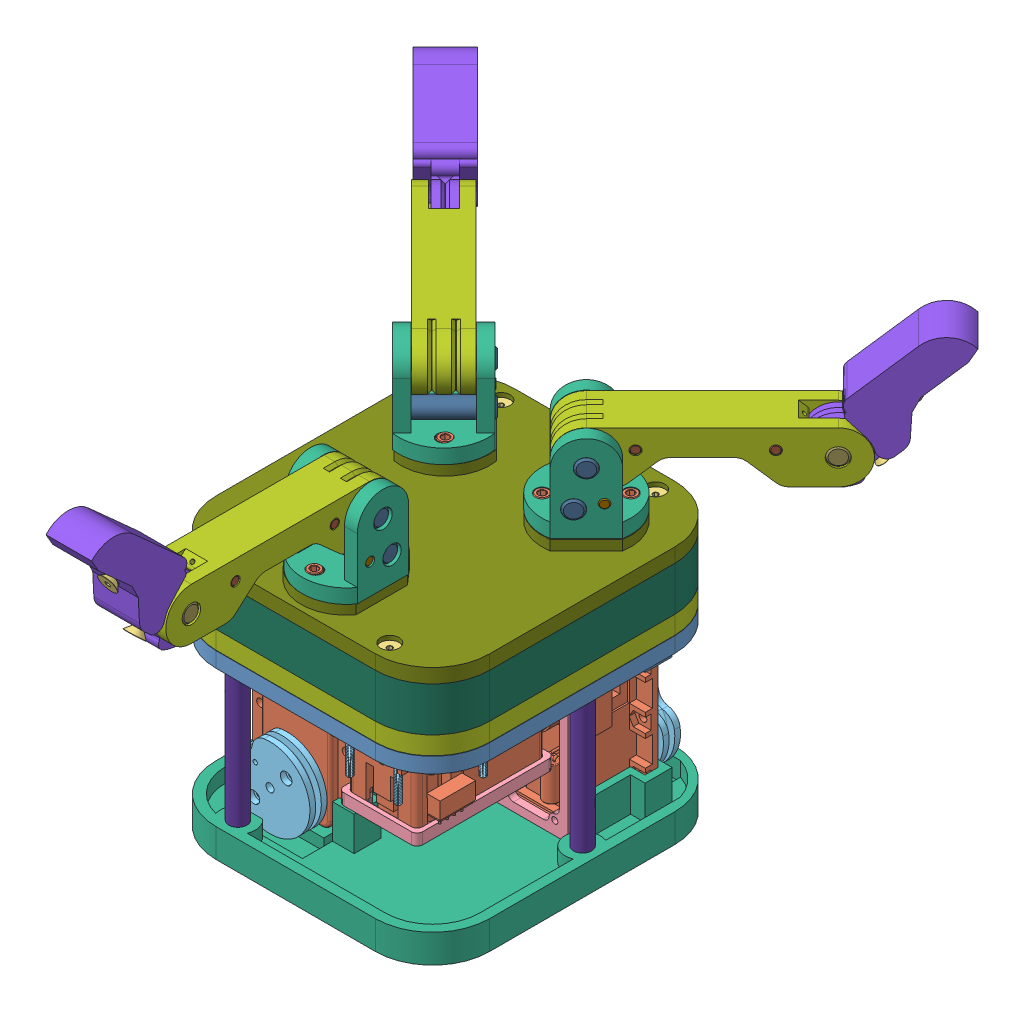
SolidWorks assembly hand_model, configuration Default. Lengths in mm.
Overall size (458.66 261.05 528.52).
145 component instances, 30 part files, 23 mates.
Components (placement in the parent):
- wrist_block_final-1: wrist_block_final [Default] at (38.9884 111.7259 8.2191) x (-1 0 0) z (0 0 1) size (96.58 286.67 158.34)
  - w1-1: w1 [Default] at (-5.748 25.854 -30.7534) size (96 184.32 158.34)
    - w_t1_test-1: w_t1_test [Default] at (30.6952 9.3465 110.579) size (96 12.88 105)
    - gear_MX-28-1: gear_MX-28 [Default] at (18.9956 62.9761 161.9587) x (-1 0 0) z (0 -1 0) size (35.6 52.23 39.77)
      - dynamixel MX-28-exposed-1: dynamixel MX-28-exposed [Back Off] at (8.6005 39.3797 35.4547) size (35.6 50.6 39.77)
      - w_g1-2: w_g1 [Default] at (8.6005 39.3797 55.9747) size (25.49 25.49 3)
      - w_ac-1: w_ac [Default] at (20.9755 51.5047 26.7047) x (0 -1 0) z (0 0 -1) size (48.25 27.65 4)
    - pulley_MX-28-1: pulley_MX-28 [Default] at (51.4952 51.1215 127.129) size (38.36 58.4 108.06)
      - dynamixel MX-28-exposed-1: dynamixel MX-28-exposed [Back Off] at origin size (35.6 50.6 39.77)
      - w_p1-1: w_p1 [Default] at (0 0 23.67) x (0.707107 -0.707107 0) z (0 0 1) size (26.25 28 6)
      - w_ac-1: w_ac [Default] at (12.375 12.125 -8.75) x (0 -1 0) z (0 0 -1) size (48.25 27.65 4)
    - pulley_MX-28-2: pulley_MX-28 [Default] at (51.4952 51.1215 92.029) x (-1 0 0) z (0 0 -1) size (38.36 58.4 108.06)
      - dynamixel MX-28-exposed-1: dynamixel MX-28-exposed [Back Off] at origin size (35.6 50.6 39.77)
      - w_p1-1: w_p1 [Default] at (0 0 23.67) x (0.707107 -0.707107 0) z (0 0 1) size (26.25 28 6)
      - w_ac-1: w_ac [Default] at (12.375 12.125 -8.75) x (0 -1 0) z (0 0 -1) size (48.25 27.65 4)
    - pulley_MX-28-3: pulley_MX-28 [Default] at (9.8952 51.1215 92.029) x (-1 0 0) z (0 0 -1) size (38.36 58.4 108.06)
      - dynamixel MX-28-exposed-1: dynamixel MX-28-exposed [Back Off] at origin size (35.6 50.6 39.77)
      - w_p1-1: w_p1 [Default] at (0 0 23.67) x (0.707107 -0.707107 0) z (0 0 1) size (26.25 28 6)
      - w_ac-1: w_ac [Default] at (12.375 12.125 -8.75) x (0 -1 0) z (0 0 -1) size (48.25 27.65 4)
    - w_b1-1: w_b1 [Default] at (30.6952 70.6215 113.079) x (-1 0 0) z (0 0 1) size (96 17 105)
  - w2-1: w2 [Default] at (-13.7396 -16.4115 -4.4526) size (96 129.36 105)
    - w_t2-1: w_t2 [Default] at (38.6868 42.912 84.2782) size (96 6.36 105)
    - w_g2-1: w_g2 [Default] at (35.3573 46.267 79.3076) x (1 0 0) z (0 1 0) size (25.39 25.39 5.6)
    - w_g3-1: w_g3 [Default] at (71.6818 49.267 106.8682) x (1 0 0) z (0 -1 0) size (25.39 25.39 14.76)
    - w_g2-2: w_g2 [Default] at (48.9868 46.267 99.0621) x (0.999627 0 -0.027307) z (0 1 0) size (25.39 25.39 5.6)
    - w_g3-2: w_g3 [Default] at (49.1868 49.267 59.6927) x (-1 0 0) z (0 -1 0) size (25.39 25.39 14.76)
    - t_b3-1: t_b3 [Default] at (60.4377 35.807 114.6932) x (-1 0 0) z (0 1 0) size (28.8 6.3 6.91)
    - t_b4-1: t_b4 [Default] at (49.1868 35.807 51.8677) x (1 0 0) z (0 1 0) size (26.95 6.4 6.91)
    - t_block-1: t_block [Default] at (73.2381 52.5646 52.8296) x (0 1 0) z (1 0 0) size (7.5 23.31 19.7)
      - t_b1-1: t_b1 [Default] at (-13.3027 14.296 -11.9013) size (7.5 5 19.7)
      - t_b2-1: t_b2 [Default] at (-13.3027 17.296 -3.2513) x (0.623302 0 0.781981) z (0.781981 0 -0.623302) size (4.4 3 4.4)
    - t_block-2: t_block [Default] at (31.6381 52.5646 52.8296) x (0 1 0) z (1 0 0) size (7.5 23.31 19.7)
      - t_b1-1: t_b1 [Default] at (-13.3027 14.296 -11.9013) size (7.5 5 19.7)
      - t_b2-1: t_b2 [Default] at (-13.3027 17.296 -3.2513) x (0.623302 0 0.781981) z (0.781981 0 -0.623302) size (4.4 3 4.4)
    - t_block-3: t_block [Default] at (45.7305 52.5646 116.8117) x (0 1 0) z (-1 0 0) size (7.5 23.31 19.7)
      - t_b1-1: t_b1 [Default] at (-13.3027 14.296 -11.9013) size (7.5 5 19.7)
      - t_b2-1: t_b2 [Default] at (-13.3027 17.296 -3.2513) x (0.623302 0 0.781981) z (0.781981 0 -0.623302) size (4.4 3 4.4)
    - t_b5-1: t_b5 [Default] at (28.3868 42.712 50.6927) x (-1 0 0) z (0 0 1) size (4 9.6 8.15)
    - t_b5-2: t_b5 [Default] at (69.9868 42.712 50.6927) x (-1 0 0) z (0 0 1) size (4 9.6 8.15)
    - t_b5-3: t_b5 [Default] at (48.9818 42.712 115.8682) x (1 0 0) z (0 0 -1) size (4 9.6 8.15)
    - t_b4-2: t_b4 [Default] at (49.1868 42.717 51.8677) x (-1 0 0) z (0 -1 0) size (26.95 6.4 6.91)
  - w_t3-1: w_t3 [Default] at (24.9472 17.3505 82.3256) size (96 15.5 105)
  - w_t4-1: w_t4 [Default] at (50.4615 57.3787 69.1823) size (96 10.4 105)
  - al_female_round_standoff-1: al_female_round_standoff [93330A483] at (51.0893 61.0755 128.9678) x (0.137901 0 0.990446) z (0 1 0) size (6.35 6.35 51.38)
  - al_female_round_standoff-2: al_female_round_standoff [93330A483] at (-17.195 61.0755 76.3256) x (0.680091 0 -0.733128) z (0 1 0) size (6.35 6.35 51.38)
  - al_female_round_standoff-3: al_female_round_standoff [93330A483] at (67.0893 61.0755 76.3256) x (0.609984 0 -0.792414) z (0 1 0) size (6.35 6.35 51.38)
  - al_female_round_standoff-4: al_female_round_standoff [93330A483] at (24.9472 61.0755 35.6835) x (1 0 0) z (0 1 0) size (6.35 6.35 51.38)
  - st_fh_sc_screw_8_32-1: st_fh_sc_screw_8_32 [92210A197] at (-17.195 96.4755 76.3256) x (0.989952 0 -0.141402) z (0 1 0) size (9.12 9.12 19.5)
  - st_fh_sc_screw_8_32-2: st_fh_sc_screw_8_32 [92210A197] at (-17.195 27.0005 76.3235) x (0.178781 0 -0.983889) z (0 -1 0) size (9.12 9.12 19.5)
  - st_fh_sc_screw_8_32-3: st_fh_sc_screw_8_32 [92210A197] at (51.0893 96.4755 128.9678) x (0.989952 0 -0.141402) z (0 1 0) size (9.12 9.12 19.5)
  - st_fh_sc_screw_8_32-4: st_fh_sc_screw_8_32 [92210A197] at (24.9472 96.4755 35.6835) x (0.989952 0 -0.141402) z (0 1 0) size (9.12 9.12 19.5)
  - st_fh_sc_screw_8_32-5: st_fh_sc_screw_8_32 [92210A197] at (67.0893 27.0005 76.3235) x (-0.751419 0 -0.659826) z (0 -1 0) size (9.12 9.12 19.5)
  - st_fh_sc_screw_8_32-6: st_fh_sc_screw_8_32 [92210A197] at (51.0893 27.0005 128.9678) x (-0.44773 0 0.894169) z (0 -1 0) size (9.12 9.12 19.5)
  - st_fh_sc_screw_8_32-7: st_fh_sc_screw_8_32 [92210A197] at (67.0893 96.4755 76.3256) x (0.989952 0 -0.141402) z (0 1 0) size (9.12 9.12 19.5)
  - st_fh_sc_screw_8_32-8: st_fh_sc_screw_8_32 [92210A197] at (24.9472 27.0005 35.6835) x (-0.751419 0 -0.659826) z (0 -1 0) size (9.12 9.12 19.5)
  - heat_sink_insert-17: heat_sink_insert [93365A120] at (52.0893 11.0005 35.6835) x (-0.837169 0 -0.546944) z (-0.546944 0 0.837169) size (4.37 3.82 4.37)
  - heat_sink_insert-18: heat_sink_insert [93365A120] at (-2.195 11.0005 128.9678) x (-0.837169 0 -0.546944) z (-0.546944 0 0.837169) size (4.37 3.82 4.37)
  - heat_sink_insert-3: heat_sink_insert [93365A120] at (52.0893 11.0005 128.9678) x (-0.837169 0 -0.546944) z (-0.546944 0 0.837169) size (4.37 3.82 4.37)
  - heat_sink_insert-4: heat_sink_insert [93365A120] at (-2.195 11.0005 35.6835) x (-0.837169 0 -0.546944) z (-0.546944 0 0.837169) size (4.37 3.82 4.37)
  - heat_sink_insert-5: heat_sink_insert [93365A120] at (39.9472 26.5005 36.5756) x (-0.837169 0 -0.546944) z (-0.546944 0 0.837169) size (4.37 3.82 4.37)
  - heat_sink_insert-6: heat_sink_insert [93365A120] at (-16.3028 26.5005 112.3256) x (-0.837169 0 -0.546944) z (-0.546944 0 0.837169) size (4.37 3.82 4.37)
  - heat_sink_insert-7: heat_sink_insert [93365A120] at (66.1378 26.5005 119.9956) x (-0.837169 0 -0.546944) z (-0.546944 0 0.837169) size (4.37 3.82 4.37)
  - heat_sink_insert-8: heat_sink_insert [93365A120] at (-16.3028 26.5005 52.3256) x (-0.973084 0 -0.230449) z (-0.230449 0 0.973084) size (4.37 3.82 4.37)
  - st_sh_screw_4_40-1: st_sh_screw_4_40 [92185A106] at (39.9472 30.5953 36.5756) x (1 0 0) z (0 1 0) size (4.65 4.65 9.43)
  - st_sh_screw_4_40-2: st_sh_screw_4_40 [92185A106] at (-16.3028 30.5953 112.3256) x (1 0 0) z (0 1 0) size (4.65 4.65 9.43)
  - st_sh_screw_4_40-3: st_sh_screw_4_40 [92185A106] at (66.1378 30.5953 119.9956) x (1 0 0) z (0 1 0) size (4.65 4.65 9.43)
  - st_sh_screw_4_40-5: st_sh_screw_4_40 [92185A106] at (-16.3028 30.5953 52.3256) x (1 0 0) z (0 1 0) size (4.65 4.65 9.43)
  - heat_sink_insert-15: heat_sink_insert [93365A120] at (24.9472 2.5005 128.3256) x (-0.837169 0 -0.546944) z (-0.546944 0 0.837169) size (4.37 3.82 4.37)
  - heat_sink_insert-16: heat_sink_insert [93365A120] at (7.9766 2.5005 65.3551) x (-0.837169 0 -0.546944) z (-0.546944 0 0.837169) size (4.37 3.82 4.37)
  - heat_sink_insert-11: heat_sink_insert [93365A120] at (-7.5798 2.5005 49.7987) x (-0.837169 0 -0.546944) z (-0.546944 0 0.837169) size (4.37 3.82 4.37)
  - heat_sink_insert-12: heat_sink_insert [93365A120] at (24.9472 2.5005 106.3256) x (-0.505917 0 -0.862582) z (-0.862582 0 0.505917) size (4.37 3.82 4.37)
  - heat_sink_insert-13: heat_sink_insert [93365A120] at (41.9177 2.5005 65.3551) x (-0.581099 0 -0.813833) z (-0.813833 0 0.581099) size (4.37 3.82 4.37)
  - heat_sink_insert-14: heat_sink_insert [93365A120] at (57.4741 2.5005 49.7987) x (-0.837169 0 -0.546944) z (-0.546944 0 0.837169) size (4.37 3.82 4.37)
  - st_fh_sc_screw_4_40-1: st_fh_sc_screw_4_40 [91253A106] at (-2.195 7.5005 128.9678) x (1 0 0) z (0 -1 0) size (6.48 6.48 6.63)
  - st_fh_sc_screw_4_40-2: st_fh_sc_screw_4_40 [91253A106] at (52.0893 7.5005 128.9678) x (1 0 0) z (0 -1 0) size (6.48 6.48 6.63)
  - st_fh_sc_screw_4_40-3: st_fh_sc_screw_4_40 [91253A106] at (52.0893 7.5005 35.6835) x (1 0 0) z (0 -1 0) size (6.48 6.48 6.63)
  - st_fh_sc_screw_4_40-4: st_fh_sc_screw_4_40 [91253A106] at (-2.195 7.5005 35.6835) x (1 0 0) z (0 -1 0) size (6.48 6.48 6.63)
  - st_hex_nut_2_56-1: st_hex_nut_2_56 [90480A003] at (13.1472 41.6693 127.6256) size (4.76 1.94 5.5)
  - st_sh_cscrew_2_56-1: st_sh_cscrew_2_56 [92196A084] at (13.1472 54.7505 127.6256) x (0.985498 0 -0.169684) z (0 1 0) size (3.56 3.56 21.57)
  - st_sh_cscrew_2_56-2: st_sh_cscrew_2_56 [92196A084] at (-10.3528 54.7505 104.3256) x (0.985498 0 -0.169684) z (0 1 0) size (3.56 3.56 21.57)
  - st_sh_cscrew_2_56-3: st_sh_cscrew_2_56 [92196A084] at (-3.8528 54.7505 127.6256) x (0.985498 0 -0.169684) z (0 1 0) size (3.56 3.56 21.57)
  - st_sh_cscrew_2_56-4: st_sh_cscrew_2_56 [92196A084] at (19.6472 54.7505 104.3256) x (0.985498 0 -0.169684) z (0 1 0) size (3.56 3.56 21.57)
  - st_hex_nut_2_56-2: st_hex_nut_2_56 [90480A003] at (-10.3528 41.6693 104.3256) size (4.76 1.94 5.5)
  - st_hex_nut_2_56-3: st_hex_nut_2_56 [90480A003] at (19.6472 41.6693 104.3256) x (0.910241 0 -0.41408) z (0.41408 0 0.910241) size (4.76 1.94 5.5)
  - st_hex_nut_2_56-5: st_hex_nut_2_56 [90480A003] at (-3.8528 41.6693 127.6256) x (0.924033 0 -0.382313) z (0.382313 0 0.924033) size (4.76 1.94 5.5)
- finger_block-1: finger_block [Default] at (-118.6928 127.742 224.9233) x (-1 0 0) z (0 0 -1) size (122.28 138.04 251.99)
  - f_k1-1: f_k1 [Default] at (-133.1387 2.8358 99.3785) size (25.4 30.39 31.13)
  - f_d1-1: f_d1 [Default] at (-133.1137 2.8358 99.3785) size (16 18 80.5)
  - f_d2-1: f_d2 [Default] at (-132.7637 2.8358 36.8785) x (1 0 0) z (0 -0.669077 0.743193) size (16 23.57 57.08)
  - 98381A475-1: 98381A475 [98381A475] at (-132.8212 -7.9267 94.8785) x (1 0 0) z (0 -0.886717 0.462312) size (25.4 3.17 3.17)
  - 98381A542-1: 98381A542 [98381A542] at (-132.5037 -9.6416 102.5535) x (1 0 0) z (0 -0.999996 0.002882) size (25.4 6.35 6.35)
  - 98381A542-2: 98381A542 [98381A542] at (-132.5037 2.8358 99.3785) x (1 0 0) z (0 -0.486508 0.873676) size (25.4 6.35 6.35)
  - heat_sink_insert-1: heat_sink_insert [93365A120] at (-133.1137 -6.1642 48.3785) x (-0.837169 0 -0.546944) z (-0.546944 0 0.837169) size (4.37 3.82 4.37)
  - heat_sink_insert-2: heat_sink_insert [93365A120] at (-133.1137 6.6358 70.6285) x (-0.837169 0 -0.546944) z (-0.546944 0 0.837169) size (4.37 3.82 4.37)
  - heat_sink_insert-3: heat_sink_insert [93365A120] at (-132.7637 18.9794 17.5168) x (-0.837169 0.493647 -0.235501) z (-0.546944 -0.755591 0.360465) size (4.37 3.82 4.37)
  - heat_sink_insert-4: heat_sink_insert [93365A120] at (-132.7637 -0.2417 26.8456) x (-0.837169 0.365948 -0.406485) z (-0.546944 -0.560131 0.622178) size (4.37 3.82 4.37)
  - st_fh_sc_screw_4_40-1: st_fh_sc_screw_4_40 [91253A106] at (-133.1137 3.9858 70.6285) x (0.988669 0 0.150109) z (0 -1 0) size (6.48 6.48 6.63)
  - st_fh_sc_screw_4_40-2: st_fh_sc_screw_4_40 [91253A106] at (-132.7637 18.1828 15.8471) x (0.988669 -0.135482 0.064633) z (0 -0.430576 -0.902554) size (6.48 6.48 6.63)
  - st_fh_sc_screw_4_40-3: st_fh_sc_screw_4_40 [91253A106] at (-133.1137 -8.0142 48.3785) x (0.988669 0 0.150109) z (0 -1 0) size (6.48 6.48 6.63)
  - st_fh_sc_screw_4_40-4: st_fh_sc_screw_4_40 [91253A106] at (-132.7637 -1.9882 25.2733) x (0.988669 -0.100435 0.11156) z (0 -0.743193 -0.669077) size (6.48 6.48 6.63)
  - dowel_1_8x5_8-1: dowel_1_8x5_8 [97395A445] at (-133.1762 4.9983 87.2035) size (15.88 3.17 3.17)
  - dowel_1_8x5_8-2: dowel_1_8x5_8 [97395A445] at (-133.0512 4.9983 52.3676) size (15.88 3.17 3.17)
  - dowel_1_4x5_8-1: dowel_1_4x5_8 [98381A539] at (-133.0512 2.8358 36.8785) size (15.88 6.35 6.35)
- finger_block-2: finger_block [Default] at (12.9136 126.3437 -98.2972) x (0.707107 0 -0.707107) z (0.707037 0.014073 0.707037) size (122.28 127.61 257.29) (flexible)
  - f_k1-1: f_k1 [Default] at (-133.1387 2.8358 99.3785) size (25.4 30.39 31.13)
  - f_d1-1: f_d1 [Default] at (-133.1137 2.8358 99.3785) size (16 18 80.5)
  - f_d2-1: f_d2 [Default] at (-132.7637 2.8358 36.8785) x (1 0 0) z (0 -0.344946 0.938623) size (16 23.57 57.08)
  - 98381A475-1: 98381A475 [98381A475] at (-132.8212 -7.9267 94.8785) x (1 0 0) z (0 -0.886717 0.462312) size (25.4 3.17 3.17)
  - 98381A542-1: 98381A542 [98381A542] at (-132.5037 -9.6416 102.5535) x (1 0 0) z (0 -0.999996 0.002882) size (25.4 6.35 6.35)
  - 98381A542-2: 98381A542 [98381A542] at (-132.5037 2.8358 99.3785) x (1 0 0) z (0 -0.486508 0.873676) size (25.4 6.35 6.35)
  - heat_sink_insert-1: heat_sink_insert [93365A120] at (-133.1137 -6.1642 48.3785) x (-0.837169 0 -0.546944) z (-0.546944 0 0.837169) size (4.37 3.82 4.37)
  - heat_sink_insert-2: heat_sink_insert [93365A120] at (-133.1137 6.6358 70.6285) x (-0.837169 0 -0.546944) z (-0.546944 0 0.837169) size (4.37 3.82 4.37)
  - heat_sink_insert-3: heat_sink_insert [93365A120] at (-132.7637 10.6273 12.9038) x (-0.837169 0.370764 -0.402096) z (-0.546944 -0.567503 0.615461) size (4.37 3.82 4.37)
  - heat_sink_insert-4: heat_sink_insert [93365A120] at (-132.7637 -3.75 28.708) x (-0.837169 0.188666 -0.513374) z (-0.546944 -0.288778 0.785786) size (4.37 3.82 4.37)
  - st_fh_sc_screw_4_40-1: st_fh_sc_screw_4_40 [91253A106] at (-133.1137 3.9858 70.6285) x (0.988669 0 0.150109) z (0 -1 0) size (6.48 6.48 6.63)
  - st_fh_sc_screw_4_40-2: st_fh_sc_screw_4_40 [91253A106] at (-132.7637 9.2672 11.6498) x (0.988669 -0.101756 0.110356) z (0 -0.735169 -0.677884) size (6.48 6.48 6.63)
  - st_fh_sc_screw_4_40-3: st_fh_sc_screw_4_40 [91253A106] at (-133.1137 -8.0142 48.3785) x (0.988669 0 0.150109) z (0 -1 0) size (6.48 6.48 6.63)
  - st_fh_sc_screw_4_40-4: st_fh_sc_screw_4_40 [91253A106] at (-132.7637 -5.9558 27.8974) x (0.988669 -0.051779 0.140896) z (0 -0.938623 -0.344946) size (6.48 6.48 6.63)
  - dowel_1_8x5_8-1: dowel_1_8x5_8 [97395A445] at (-133.1762 4.9983 87.2035) x (1 0 0) z (0 -0.014073 0.999901) size (15.88 3.17 3.17)
  - dowel_1_8x5_8-2: dowel_1_8x5_8 [97395A445] at (-133.0512 4.9983 52.3676) x (1 0 0) z (0 -0.014073 0.999901) size (15.88 3.17 3.17)
  - dowel_1_4x5_8-1: dowel_1_4x5_8 [98381A539] at (-133.0512 2.8358 36.8785) x (1 0 0) z (0 -0.014073 0.999901) size (15.88 6.35 6.35)
- finger_block-3: finger_block [Default] at (202.9184 127.742 89.3819) x (0.707107 0 0.707107) z (-0.707107 0 0.707107) size (122.28 138.04 251.99)
  - f_k1-1: f_k1 [Default] at (-133.1387 2.8358 99.3785) size (25.4 30.39 31.13)
  - f_d1-1: f_d1 [Default] at (-133.1137 2.8358 99.3785) size (16 18 80.5)
  - f_d2-1: f_d2 [Default] at (-132.7637 2.8358 36.8785) x (1 0 0) z (0 -0.669077 0.743193) size (16 23.57 57.08)
  - 98381A475-1: 98381A475 [98381A475] at (-132.8212 -7.9267 94.8785) x (1 0 0) z (0 -0.886717 0.462312) size (25.4 3.17 3.17)
  - 98381A542-1: 98381A542 [98381A542] at (-132.5037 -9.6416 102.5535) x (1 0 0) z (0 -0.999996 0.002882) size (25.4 6.35 6.35)
  - 98381A542-2: 98381A542 [98381A542] at (-132.5037 2.8358 99.3785) x (1 0 0) z (0 -0.486508 0.873676) size (25.4 6.35 6.35)
  - heat_sink_insert-1: heat_sink_insert [93365A120] at (-133.1137 -6.1642 48.3785) x (-0.837169 0 -0.546944) z (-0.546944 0 0.837169) size (4.37 3.82 4.37)
  - heat_sink_insert-2: heat_sink_insert [93365A120] at (-133.1137 6.6358 70.6285) x (-0.837169 0 -0.546944) z (-0.546944 0 0.837169) size (4.37 3.82 4.37)
  - heat_sink_insert-3: heat_sink_insert [93365A120] at (-132.7637 18.9794 17.5168) x (-0.837169 0.493647 -0.235501) z (-0.546944 -0.755591 0.360465) size (4.37 3.82 4.37)
  - heat_sink_insert-4: heat_sink_insert [93365A120] at (-132.7637 -0.2417 26.8456) x (-0.837169 0.365948 -0.406485) z (-0.546944 -0.560131 0.622178) size (4.37 3.82 4.37)
  - st_fh_sc_screw_4_40-1: st_fh_sc_screw_4_40 [91253A106] at (-133.1137 3.9858 70.6285) x (0.988669 0 0.150109) z (0 -1 0) size (6.48 6.48 6.63)
  - st_fh_sc_screw_4_40-2: st_fh_sc_screw_4_40 [91253A106] at (-132.7637 18.1828 15.8471) x (0.988669 -0.135482 0.064633) z (0 -0.430576 -0.902554) size (6.48 6.48 6.63)
  - st_fh_sc_screw_4_40-3: st_fh_sc_screw_4_40 [91253A106] at (-133.1137 -8.0142 48.3785) x (0.988669 0 0.150109) z (0 -1 0) size (6.48 6.48 6.63)
  - st_fh_sc_screw_4_40-4: st_fh_sc_screw_4_40 [91253A106] at (-132.7637 -1.9882 25.2733) x (0.988669 -0.100435 0.11156) z (0 -0.743193 -0.669077) size (6.48 6.48 6.63)
  - dowel_1_8x5_8-1: dowel_1_8x5_8 [97395A445] at (-133.1762 4.9983 87.2035) size (15.88 3.17 3.17)
  - dowel_1_8x5_8-2: dowel_1_8x5_8 [97395A445] at (-133.0512 4.9983 52.3676) size (15.88 3.17 3.17)
  - dowel_1_4x5_8-1: dowel_1_4x5_8 [98381A539] at (-133.0512 2.8358 36.8785) size (15.88 6.35 6.35)
- st_sh_screw_4_40-1: st_sh_screw_4_40 [92185A106] at (31.0118 105.263 73.5742) x (1 0 0) z (0 -1 0) size (4.65 4.65 9.43)
- st_sh_screw_4_40-2: st_sh_screw_4_40 [92185A106] at (-2.9293 105.263 73.5742) x (0.980869 0 0.19467) z (0 -1 0) size (4.65 4.65 9.43)
- st_sh_screw_4_40-3: st_sh_screw_4_40 [92185A106] at (46.5682 105.263 58.0178) x (1 0 0) z (0 -1 0) size (4.65 4.65 9.43)
- st_sh_screw_4_40-4: st_sh_screw_4_40 [92185A106] at (14.0413 105.263 114.5447) x (1 0 0) z (0 -1 0) size (4.65 4.65 9.43)
- st_sh_screw_4_40-5: st_sh_screw_4_40 [92185A106] at (-18.4857 105.263 58.0178) x (1 0 0) z (0 -1 0) size (4.65 4.65 9.43)
- st_sh_screw_4_40-6: st_sh_screw_4_40 [92185A106] at (14.0413 105.263 136.5447) x (0.929189 0 -0.369604) z (0 -1 0) size (4.65 4.65 9.43)
Mates (geometry in assembly coordinates):
- Concentric1: concentric aligned: cylinder of wrist_block_final-1/w_t4-1 through (14.0413 109.2254 125.5447) axis (0 -1 0) radius 15.5657; cylinder of ? through (14.0413 139.5778 125.5447) axis (0 -1 0) radius 15.5657
- Coincident1: coincident aligned: plane of wrist_block_final-1/w_t4-1 through (26.7413 109.2254 77.4014) normal (1 0 0); plane of ? through (26.7413 130.5778 125.5447) normal (1 0 0)
- Coincident2: coincident anti-aligned: plane of wrist_block_final-1/w_t4-1 through (-11.4731 109.2254 77.4014) normal (0 1 0); plane of ? through (14.0413 109.2254 125.5447) normal (0 -1 0)
- Parallel2: parallel aligned: cylinder of wrist_block_final-1/w_t4-1 through (-10.7075 109.2254 65.796) axis (0 -1 0) radius 15.5657; cylinder of ? through (-10.7075 139.5778 65.796) axis (0 -1 0) radius 15.5657
- Coincident4: coincident anti-aligned: plane of wrist_block_final-1/w_t4-1 through (-11.4731 109.2254 77.4014) normal (0 1 0); plane of ? through (-10.7075 109.2254 65.796) normal (0 -1 0)
- Coincident7: coincident aligned: plane of wrist_block_final-1/w_t4-1 through (3.6926 109.2254 62.2356) normal (0.707107 0 -0.707107); plane of ? through (-1.7272 130.5778 56.8158) normal (0.707107 0 -0.707107)
- Concentric4: concentric aligned: cylinder of wrist_block_final-1/w_t4-1 through (-10.7075 109.2254 65.796) axis (0 -1 0) radius 15.5657; cylinder of ? through (-10.7075 139.5778 65.796) axis (0 -1 0) radius 15.5657
- Coincident8: coincident anti-aligned: plane of wrist_block_final-1/w_t4-1 through (-11.4731 109.2254 77.4014) normal (0 1 0); plane of ? through (38.79 109.2254 65.796) normal (0 -1 0)
- Coincident9: coincident aligned: plane of wrist_block_final-1/w_t4-1 through (-1.1245 109.2254 87.75) normal (-0.707107 0 -0.707107); plane of ? through (29.8097 130.5778 56.8158) normal (-0.707107 0 -0.707107)
- Concentric5: concentric aligned: cylinder of wrist_block_final-1/w_t4-1 through (38.79 109.2254 65.796) axis (0 -1 0) radius 15.5657; cylinder of ? through (38.79 139.5778 65.796) axis (0 -1 0) radius 15.5657
- Concentric6: concentric anti-aligned: cylinder of ? through (-2.9293 104.9828 73.5742) axis (0 1 0) radius 1.5; cylinder of st_sh_screw_4_40-2 through (-2.9293 114.4578 73.5742) axis (0 -1 0) radius 2.3241
- Concentric7: concentric anti-aligned: cylinder of ? through (-2.9293 112.1254 73.5742) axis (0 1 0) radius 2.35; circle of st_sh_screw_4_40-2
- Concentric8: concentric anti-aligned: circle of ?; cylinder of st_sh_screw_4_40-5 through (-18.4857 114.4578 58.0178) axis (0 -1 0) radius 2.3241
- Coincident10: coincident anti-aligned: plane of ? through (-10.7075 114.2254 65.796) normal (0 1 0); circle of st_sh_screw_4_40-5
- Coincident11: coincident anti-aligned: plane of ? through (-10.7075 114.2254 65.796) normal (0 1 0); circle of st_sh_screw_4_40-2
- Concentric11: concentric anti-aligned: cylinder of ? through (31.0118 112.1254 73.5742) axis (0 1 0) radius 2.35; cylinder of st_sh_screw_4_40-1 through (31.0118 114.4578 73.5742) axis (0 -1 0) radius 2.3241
- Coincident12: coincident anti-aligned: plane of ? through (38.79 114.2254 65.796) normal (0 1 0); circle of st_sh_screw_4_40-1
- Concentric13: concentric anti-aligned: cylinder of ? through (14.0413 112.1254 114.5447) axis (0 1 0) radius 2.35; cylinder of st_sh_screw_4_40-4 through (14.0413 114.4578 114.5447) axis (0 -1 0) radius 2.3241
- Coincident13: coincident anti-aligned: plane of ? through (14.0413 114.2254 125.5447) normal (0 1 0); circle of st_sh_screw_4_40-4
- Concentric14: concentric anti-aligned: cylinder of ? through (46.5682 112.1254 58.0178) axis (0 1 0) radius 2.35; cylinder of st_sh_screw_4_40-3 through (46.5682 114.4578 58.0178) axis (0 -1 0) radius 2.3241
- Coincident14: coincident anti-aligned: plane of ? through (38.79 114.2254 65.796) normal (0 1 0); circle of st_sh_screw_4_40-3
- Concentric16: concentric anti-aligned: cylinder of ? through (14.0413 112.1254 136.5447) axis (0 1 0) radius 2.35; cylinder of st_sh_screw_4_40-6 through (14.0413 114.4578 136.5447) axis (0 -1 0) radius 2.3241
- Coincident16: coincident anti-aligned: plane of ? through (14.0413 114.2254 125.5447) normal (0 1 0); circle of st_sh_screw_4_40-6
